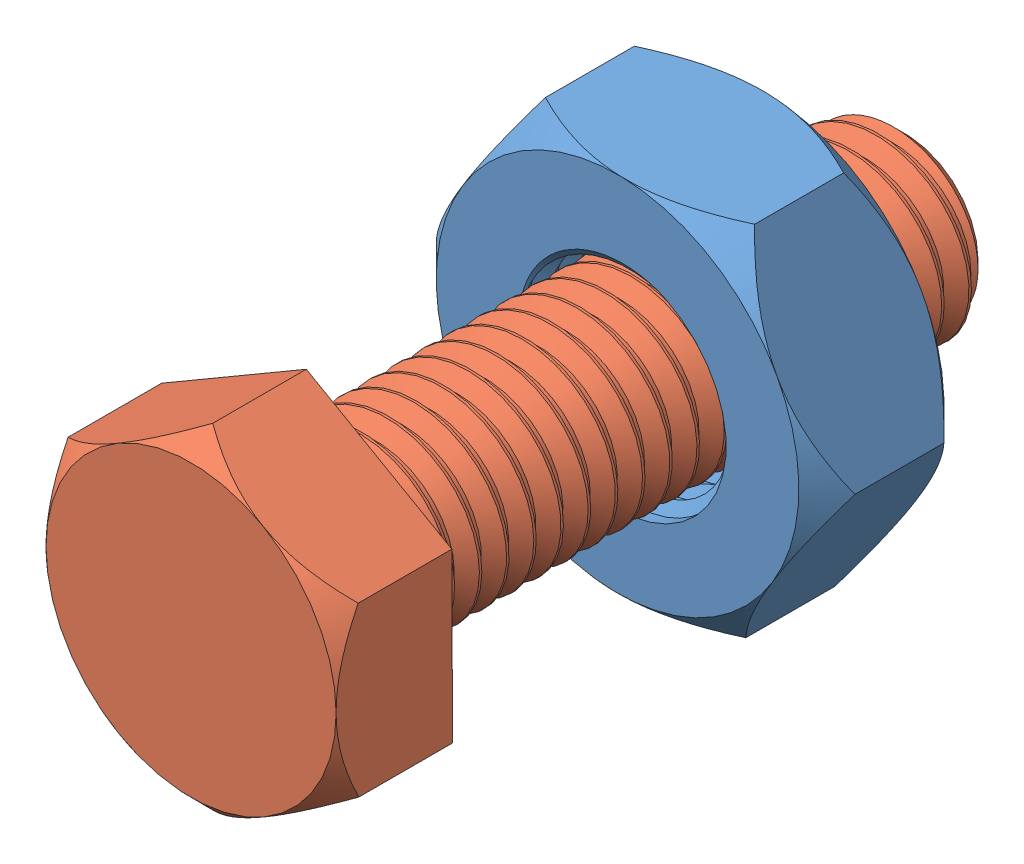
SolidWorks assembly Assem1, configuration Default. Lengths in mm.
Overall size (25.39 22.58 39.98).
2 component instances, 2 part files, 2 mates.
Components (placement in the parent):
- nut-1: nut [Default] at (10.6401 16.0106 13.0041) size (25.39 22.58 9.03)
- screw-1: screw [Default] at (10.6401 16.0106 38.1261) size (17.89 18.48 39.98)
Mates (geometry in assembly coordinates):
- Parallel2: parallel: plane of nut-1 through (10.6401 16.0106 13.0041) normal (0 0 -1); plane of ? through (-7.0312 16.448 5.1261) normal (0 0 -1)
- Concentric1: concentric: cylinder of assembly; cylinder of assembly; cylinder of nut-1 through (10.6401 16.0106 21.0041) axis (0 0 -1) radius 5.9889; cylinder of screw-1 through (10.6401 16.0106 5.1261) axis (0 0 1) radius 4.2374
